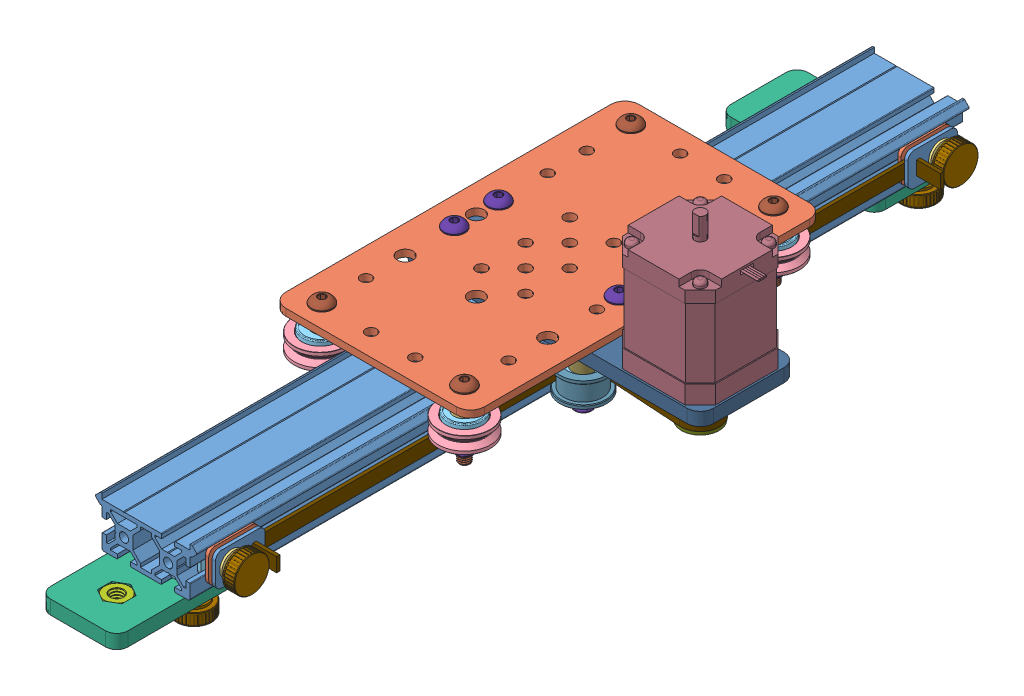
SolidWorks assembly c30049_rev_1, configuration Default. Lengths in mm.
Overall size (150.16 102.06 380.76).
102 component instances, 27 part files, 0 mates.
Components (placement in the parent):
- B17022_350-1: B17022_350 [Default] x (0 1 0) z (0 0 -1) size (22.38 45.94 350)
- C30047_ASM-1: C30047_ASM [Default] at (0.375 25.025 -181.6) size (142.28 88.15 163.5)
  - CS_PLATE-1: CS_PLATE [Default] x (0 -1 0) z (-1 0 0) size (3.17 160 90)
  - SPACER_192_375_250-1: SPACER_192_375_250 [Default] at (32.3 -9.525 70) size (9.53 6.35 9.53)
  - B30037_ASM-1: B30037_ASM [Default] at (32.3 -15.025 70) size (23.5 11 23.5)
    - B17021-1: B17021 [Default] at origin size (23.5 7.5 23.5)
    - BEARING_5_16_5-1: BEARING_5_16_5 [Default] at (0 3 0) x (-1 0 0) z (0 0 1) size (16 5 16)
    - BEARING_5_16_5-2: BEARING_5_16_5 [Default] at (0 -3 0) x (-1 0 0) z (0 0 1) size (16 5 16)
    - B18026-1: B18026 [Default] at (0 -0.5 0) size (10 1 10)
  - SPACER_192_375_250-2: SPACER_192_375_250 [Default] at (32.3 -9.525 -70) size (9.53 6.35 9.53)
  - B30037_ASM-2: B30037_ASM [Default] at (32.3 -15.025 -70) size (23.5 11 23.5)
    - B17021-1: B17021 [Default] at origin size (23.5 7.5 23.5)
    - BEARING_5_16_5-1: BEARING_5_16_5 [Default] at (0 3 0) x (-1 0 0) z (0 0 1) size (16 5 16)
    - BEARING_5_16_5-2: BEARING_5_16_5 [Default] at (0 -3 0) x (-1 0 0) z (0 0 1) size (16 5 16)
    - B18026-1: B18026 [Default] at (0 -0.5 0) size (10 1 10)
  - B18001-001-1: B18001-001 [Default] at (-32.3 -3.175 -70) x (0 0 -1) z (-1 0 0) size (10.08 7.62 7.94)
  - B18001-001-2: B18001-001 [Default] at (-32.3 -3.175 70) x (0 0 -1) z (-1 0 0) size (10.08 7.62 7.94)
  - B30037_ASM-3: B30037_ASM [Default] at (-33.0938 -15.025 70) size (23.5 11 23.5)
    - B17021-1: B17021 [Default] at origin size (23.5 7.5 23.5)
    - BEARING_5_16_5-1: BEARING_5_16_5 [Default] at (0 3 0) x (-1 0 0) z (0 0 1) size (16 5 16)
    - BEARING_5_16_5-2: BEARING_5_16_5 [Default] at (0 -3 0) x (-1 0 0) z (0 0 1) size (16 5 16)
    - B18026-1: B18026 [Default] at (0 -0.5 0) size (10 1 10)
  - B30037_ASM-4: B30037_ASM [Default] at (-33.0938 -15.025 -70) size (23.5 11 23.5)
    - B17021-1: B17021 [Default] at origin size (23.5 7.5 23.5)
    - BEARING_5_16_5-1: BEARING_5_16_5 [Default] at (0 3 0) x (-1 0 0) z (0 0 1) size (16 5 16)
    - BEARING_5_16_5-2: BEARING_5_16_5 [Default] at (0 -3 0) x (-1 0 0) z (0 0 1) size (16 5 16)
    - B18026-1: B18026 [Default] at (0 -0.5 0) size (10 1 10)
  - HNM5NL-1: HNM5NL [Default] at (-33.0938 -20.525 70) x (-1 0 0) z (0 0 1) size (8 5.15 9.24)
  - HNM5NL-2: HNM5NL [Default] at (-33.0938 -20.525 -70) x (-1 0 0) z (0 0 1) size (8 5.15 9.24)
  - HNM5NL-3: HNM5NL [Default] at (32.3 -20.525 -70) x (-1 0 0) z (0 0 1) size (8 5.15 9.24)
  - HNM5NL-4: HNM5NL [Default] at (32.3 -20.525 70) x (-1 0 0) z (0 0 1) size (8 5.15 9.24)
  - SPACER_192_312_125-1: SPACER_192_312_125 [Default] at (-32.3 -6.35 -10) size (7.94 3.17 7.94)
  - SPACER_192_312_125-2: SPACER_192_312_125 [Default] at (-32.3 -6.35 10) size (7.94 3.17 7.94)
  - C17045-1: C17045 [Default] at (69.13 -12.35 0) x (0 0 -1) z (1 0 0) size (44 6 136)
  - SPACER_192_312_125-3: SPACER_192_312_125 [Default] at (32.3 -6.35 0) size (7.94 3.17 7.94)
  - HNM5NL-5: HNM5NL [Default] at (-32.3 -12.35 10) x (-1 0 0) z (0 0 1) size (8 5.15 9.24)
  - HNM5NL-6: HNM5NL [Default] at (-32.3 -12.35 -10) x (-1 0 0) z (0 0 1) size (8 5.15 9.24)
  - HNM5NL-7: HNM5NL [Default] at (32.3 -12.35 0) x (-1 0 0) z (0 0 1) size (8 5.15 9.24)
  - BHCSM530S-1: BHCSM530S [Default] at (31.13 -36.35 15) x (1 0 0) z (0 -1 0) size (9.51 9.51 32.9)
  - BHCSM530S-2: BHCSM530S [Default] at (31.13 -36.35 -15) x (1 0 0) z (0 -1 0) size (9.51 9.51 32.9)
  - SPACER_192_375_312-1: SPACER_192_375_312 [Default] at (31.13 -20.2875 -15) size (9.53 7.94 9.53)
  - SPACER_192_375_312-2: SPACER_192_375_312 [Default] at (31.13 -20.2875 15) size (9.53 7.94 9.53)
  - B10-10001-1: B10-10001 [Default] at (69.13 -6.35 0) x (-1 0 0) z (0 0 1) size (49.3 82 42.3)
  - B30041_ASM-1: B30041_ASM [Default] at (31.13 -24.2875 -15) x (0 -1 0) z (0 0 1) size (12.6 21 21)
    - B17023-1: B17023 [Default] at origin size (11.2 21 21)
    - BEARING_5_16_5-1: BEARING_5_16_5 [Default] at (-1.5 0 0) x (0 1 0) z (0 0 1) size (16 5 16)
    - B18026-1: B18026 [Default] at (2 0 0) x (0 1 0) z (0 0 1) size (10 1 10)
    - BEARING_5_16_5-2: BEARING_5_16_5 [Default] at (4.5 0 0) x (0 1 0) z (0 0 1) size (16 5 16)
  - HNM5NL-8: HNM5NL [Default] at (31.13 -31.2875 -15) x (-1 0 0) z (0 0 1) size (8 5.15 9.24)
  - B30041_ASM-2: B30041_ASM [Default] at (31.13 -24.2875 15) x (0 -1 0) z (0 0 1) size (12.6 21 21)
    - B17023-1: B17023 [Default] at origin size (11.2 21 21)
    - BEARING_5_16_5-1: BEARING_5_16_5 [Default] at (-1.5 0 0) x (0 1 0) z (0 0 1) size (16 5 16)
    - B18026-1: B18026 [Default] at (2 0 0) x (0 1 0) z (0 0 1) size (10 1 10)
    - BEARING_5_16_5-2: BEARING_5_16_5 [Default] at (4.5 0 0) x (0 1 0) z (0 0 1) size (16 5 16)
  - HNM5NL-9: HNM5NL [Default] at (31.13 -31.2875 15) x (-1 0 0) z (0 0 1) size (8 5.15 9.24)
  - PHMSM310S-1: PHMSM310S [Default] at (84.63 -2.35 -15.5) x (1 0 0) z (0 -1 0) size (6 6 12.47)
  - PHMSM310S-2: PHMSM310S [Default] at (53.63 -2.35 -15.5) x (1 0 0) z (0 -1 0) size (6 6 12.47)
  - PHMSM310S-3: PHMSM310S [Default] at (53.63 -2.35 15.5) x (1 0 0) z (0 -1 0) size (6 6 12.47)
  - PHMSM310S-4: PHMSM310S [Default] at (84.63 -2.35 15.5) x (1 0 0) z (0 -1 0) size (6 6 12.47)
  - A_6T16M020DF6005-1: A_6T16M020DF6005 [Default] at (69.13 -24.2875 0) x (-1 0 0) z (0 1 0) size (17 17 17.5)
  - BHCSM530S-3: BHCSM530S [Default] at (32.3 -30 -70) x (1 0 0) z (0 -1 0) size (9.51 9.51 32.9)
  - BHCSM530S-4: BHCSM530S [Default] at (-32.3 -30 -70) x (1 0 0) z (0 -1 0) size (9.51 9.51 32.9)
  - BHCSM530S-5: BHCSM530S [Default] at (-32.3 -30 70) x (1 0 0) z (0 -1 0) size (9.51 9.51 32.9)
  - BHCSM530S-6: BHCSM530S [Default] at (32.3 -30 70) x (1 0 0) z (0 -1 0) size (9.51 9.51 32.9)
  - BHCSM520S-1: BHCSM520S [Default] at (-32.3 -20 -10) x (1 0 0) z (0 -1 0) size (9.51 9.51 22.9)
  - BHCSM520S-2: BHCSM520S [Default] at (-32.3 -20 10) x (1 0 0) z (0 -1 0) size (9.51 9.51 22.9)
  - BHCSM520S-3: BHCSM520S [Default] at (32.3 -20 0) x (1 0 0) z (0 -1 0) size (9.51 9.51 22.9)
- CS_BELT-1: CS_BELT [Default] at origin size (56.85 6.35 302.25)
- B17048-1: B17048 [Default] at (24.5468 0 -335.6) x (0 1 0) z (0 0 1) size (15 1.5 22.5)
- B17047-1: B17047 [Default] at (21.5 0 -335.6) x (0 1 0) z (0 0 1) size (15 1.5 22.5)
- FLW10SS-1: FLW10SS [Default] at (25.5628 0 -335.6) x (0 -1 0) z (-1 0 0) size (11.11 11.11 1.02)
- SHMSM510S-1: SHMSM510S [Default] at (15.5628 0 -335.6) x (0 -1 0) z (-1 0 0) size (8.5 8.5 15.15)
- B17048-2: B17048 [Default] at (24.5468 0 -14.4) x (0 -1 0) z (0 0 -1) size (15 1.5 22.5)
- FLW10SS-2: FLW10SS [Default] at (24.5468 0 -14.4) x (0 1 0) z (1 0 0) size (11.11 11.11 1.02)
- SHMSM510S-2: SHMSM510S [Default] at (15.5628 0 -14.4) x (0 -1 0) z (-1 0 0) size (8.5 8.5 15.15)
- B17047-2: B17047 [Default] at (21.5 0 -14.4) x (0 -1 0) z (0 0 -1) size (15 1.5 22.5)
- HNKK55-1: HNKK55 [Default] at (18 0 -14.4) x (0 -1 0) z (0 0 -1) size (10 1.6 15)
- HNKK55-2: HNKK55 [Default] at (18 0 -335.6) x (0 -1 0) z (0 0 -1) size (10 1.6 15)
- 30048_ASM-1: 30048_ASM [Default] at (0 -16.35 -39.243) x (-1 0 0) z (0 0 -1) size (36 20.17 70.5)
  - B17046-1: B17046 [Default] at origin size (35 6.35 70)
  - HN2520MS-1: HN2520MS [Default] at (0 1.35 -52.5) x (-1 0 0) z (0 0 -1) size (11.11 4.76 14.11)
  - FLW10SS-1: FLW10SS [Default] at (10 0 -7.5) x (1 0 0) z (0 -1 0) size (11.11 11.11 1.02)
  - FLW10SS-2: FLW10SS [Default] at (-10 0 -27.5) x (1 0 0) z (0 -1 0) size (11.11 11.11 1.02)
  - SHMSM512S-1: SHMSM512S [Default] at (10 10.984 -7.5) x (-1 0 0) z (0 1 0) size (8.5 8.5 17.15)
  - SHMSM512S-2: SHMSM512S [Default] at (-10 10.984 -27.5) x (-1 0 0) z (0 1 0) size (8.5 8.5 17.15)
  - HNKK55-1: HNKK55 [Default] at (10 8.9406 -7.5) x (-1 0 0) z (0 0 1) size (10 1.6 15)
  - HNKK55-2: HNKK55 [Default] at (-10 8.9406 -27.5) x (-1 0 0) z (0 0 1) size (10 1.6 15)
  - B17036-1: B17036 [Default] at (10 -5.79 -7.5) size (16 6.5 16)
  - B17036-2: B17036 [Default] at (-10 -5.79 -27.5) size (16 6.5 16)
- 30048_ASM-2: 30048_ASM [Default] at (17.5 -16.35 -329.9346) x (0 0 -1) z (1 0 0) size (36 20.17 70.5)
  - B17046-1: B17046 [Default] at origin size (35 6.35 70)
  - HN2520MS-1: HN2520MS [Default] at (0 1.35 -52.5) x (-1 0 0) z (0 0 -1) size (11.11 4.76 14.11)
  - FLW10SS-1: FLW10SS [Default] at (10 0 -7.5) x (1 0 0) z (0 -1 0) size (11.11 11.11 1.02)
  - FLW10SS-2: FLW10SS [Default] at (-10 0 -27.5) x (1 0 0) z (0 -1 0) size (11.11 11.11 1.02)
  - SHMSM512S-1: SHMSM512S [Default] at (10 10.984 -7.5) x (-1 0 0) z (0 1 0) size (8.5 8.5 17.15)
  - SHMSM512S-2: SHMSM512S [Default] at (-10 10.984 -27.5) x (-1 0 0) z (0 1 0) size (8.5 8.5 17.15)
  - HNKK55-1: HNKK55 [Default] at (10 8.9406 -7.5) x (-1 0 0) z (0 0 1) size (10 1.6 15)
  - HNKK55-2: HNKK55 [Default] at (-10 8.9406 -27.5) x (-1 0 0) z (0 0 1) size (10 1.6 15)
  - B17036-1: B17036 [Default] at (10 -5.79 -7.5) size (16 6.5 16)
  - B17036-2: B17036 [Default] at (-10 -5.79 -27.5) size (16 6.5 16)
- B17036-1: B17036 [Default] at (30.3368 0 -335.6) x (0 1 0) z (0 0 1) size (16 6.5 16)
- B17036-2: B17036 [Default] at (30.3368 0 -14.4) x (0 1 0) z (0 0 1) size (16 6.5 16)
